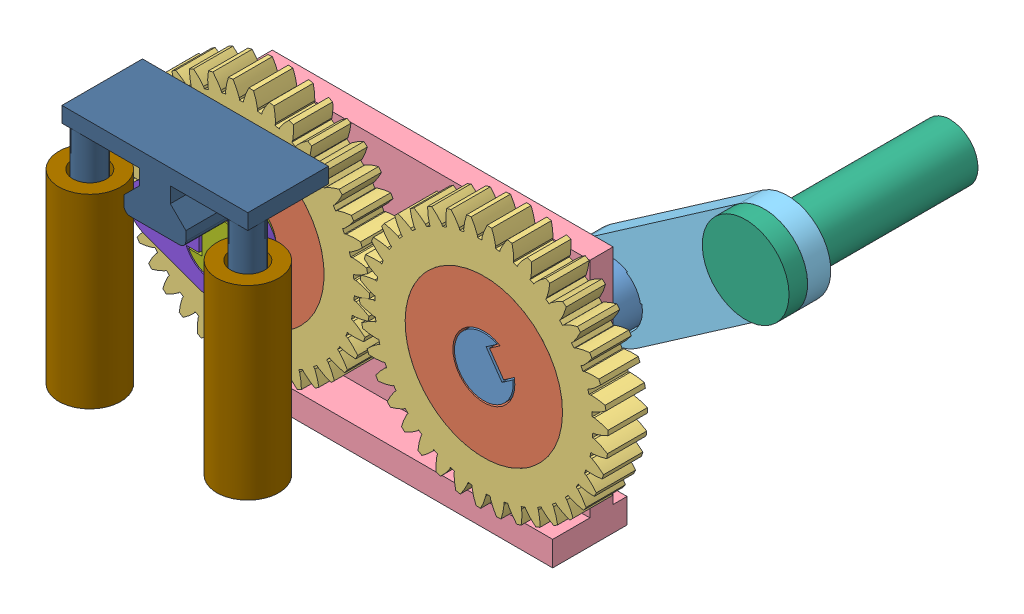
SolidWorks assembly Assem, configuration Default. Lengths in mm.
Overall size (196.54 112.49 136.7).
14 component instances, 10 part files, 30 mates.
Components (placement in the parent):
- crankShaft-1: crankShaft [Default] at (93.481 50.8 17) x (0.570054 -0.821607 0) z (-0.821607 -0.570054 0) size (19 48.7 24.5)
- gear insert-1: gear insert [Default] at (93.481 50.8 17) x (0.570054 -0.821607 0) z (0 0 1) size (50.8 50.8 12.7)
- gear insert-2: gear insert [Default] at (16.519 50.8 17) x (0.999718 0.023754 0) z (0 0 1) size (50.8 50.8 12.7)
- Gear System-1: Gear System [Default] at (25.581 50.8 17) x (0 1 0) z (0 0 1) size (112.49 184 12.7)
  - Gear Design Tutorial-1: Gear Design Tutorial [Default] at (0 9.062 0) x (0.947724 0.319093 0) z (0 0 1) size (80.19 80.19 12.7)
  - Gear Design Tutorial-2: Gear Design Tutorial [Default] at (0 -67.9 0) x (0.791148 0.611625 0) z (0 0 1) size (80.19 80.19 12.7)
- panelStand-1: panelStand [Default] at (55 0 4.5) size (110 80 24)
- turningHandleConnector-1: turningHandleConnector [Default] at (93.481 50.8 -11.5) x (-0.570054 0.821607 0) z (-0.821607 -0.570054 0) size (28 7.5 88)
- turningHandle-1: turningHandle [Default] at (142.7774 85.0032 -11.5) x (0.993504 0.113802 0) z (-0.113802 0.993504 0) size (28 66 28)
- crackArmShaft-1: crackArmShaft [Default] at (16.519 50.8 4.5) x (0.006197 -0.999981 0) z (0 0 -1) size (30 30 41.2)
- crackArmCam-1: crackArmCam [Default] at (16.519 50.8 33.7) x (-0.006197 0.999981 0) z (0 0 1) size (30 43 6)
- camFollowerAligningShaftHolder-1: camFollowerAligningShaftHolder [Default] at (-8.2022 8 55.2) size (20 60 20)
- camFollowerWithAligningShaft-1: camFollowerWithAligningShaft [Default] at (17.2978 65.8 33.7) x (1 0 0) z (0 -1 0) size (60 26 35)
- camFollowerAligningShaftHolder-3: camFollowerAligningShaftHolder [Default] at (42.7978 8 55.2) size (20 60 20)
Mates (geometry in assembly coordinates):
- Concentric1: concentric: cylinder of Gear System-1/Gear Design Tutorial-1 through (16.519 50.8 17) axis (0 0 1) radius 25.4; cylinder of panelStand-1 through (16.519 50.8 12) axis (0 0 -1) radius 10.5
- Concentric2: concentric: cylinder of Gear System-1/Gear Design Tutorial-2 through (93.481 50.8 17) axis (0 0 1) radius 25.4; cylinder of panelStand-1 through (93.481 50.8 12) axis (0 0 -1) radius 10.5
- Concentric3: concentric: cylinder of gear insert-2 through (16.519 50.8 29.7) axis (0 0 -1) radius 25.4; cylinder of Gear System-1/Gear Design Tutorial-1 through (16.519 50.8 17) axis (0 0 1) radius 25.4
- Coincident1: coincident: plane of gear insert-2 through (16.519 50.8 17) normal (0 0 -1); plane of Gear System-1/Gear Design Tutorial-1 through (16.519 50.8 17) normal (0 0 -1)
- Concentric4: concentric: cylinder of gear insert-1 through (93.481 50.8 29.7) axis (0 0 -1) radius 25.4; cylinder of Gear System-1/Gear Design Tutorial-2 through (93.481 50.8 17) axis (0 0 1) radius 25.4
- Coincident2: coincident: plane of gear insert-1 through (93.481 50.8 17) normal (0 0 -1); plane of Gear System-1/Gear Design Tutorial-2 through (93.481 50.8 17) normal (0 0 -1)
- Coincident4: coincident: plane of gear insert-1 through (93.481 50.8 29.7) normal (0 0 1); plane of crankShaft-1 through (93.481 50.8 29.7) normal (0 0 1)
- Concentric7: concentric: cylinder of crankShaft-1 through (93.481 50.8 29.7) axis (0 0 -1) radius 9.5; cylinder of panelStand-1 through (93.481 50.8 12) axis (0 0 -1) radius 10.5
- Parallel2: parallel: line of gear insert-1 through (99.8693 50.3638 29.7) axis (-0.570054 0.821607 0); line of crankShaft-1 through (99.3327 49.383 29.7) axis (-0.570054 0.821607 0)
- Concentric8: concentric: cylinder of crankShaft-1 through (93.481 50.8 29.7) axis (0 0 -1) radius 9.5; cylinder of turningHandleConnector-1 through (93.481 50.8 -19) axis (0 0 1) radius 10
- Coincident6: coincident: plane of crankShaft-1 through (93.481 50.8 -19) normal (0 0 -1); plane of turningHandleConnector-1 through (93.481 50.8 -19) normal (0 0 -1)
- Parallel4: parallel: line of crankShaft-1 through (99.3327 49.383 -19) axis (-0.570054 0.821607 0); line of turningHandleConnector-1 through (95.3088 56.9367 -19) axis (0.570054 -0.821607 0)
- Coincident8: coincident: plane of turningHandleConnector-1 through (93.481 50.8 -11.5) normal (0 0 1); plane of turningHandle-1 through (142.7774 85.0032 -11.5) normal (0 0 -1)
- Concentric9: concentric: cylinder of turningHandleConnector-1 through (142.7774 85.0032 -19) axis (0 0 1) radius 10; cylinder of turningHandle-1 through (142.7774 85.0032 -71.5) axis (0 0 1) radius 9
- Coincident10: coincident: plane of panelStand-1 through (55 0 4.5) normal (0 0 -1); plane of crackArmShaft-1 through (16.519 50.8 4.5) normal (0 0 1)
- Concentric10: concentric: cylinder of panelStand-1 through (16.519 50.8 12) axis (0 0 -1) radius 10.5; cylinder of crackArmShaft-1 through (16.519 50.8 -1.5) axis (0 0 1) radius 15
- Parallel3: parallel: line of crackArmShaft-1 through (12.547 46.2753 39.7) axis (-0.006197 0.999981 0); plane of gear insert-2 through (16.519 50.8 29.7) normal (0 0 1)
- Distance2: distance = 10 mm: plane of gear insert-2 through (16.519 50.8 29.7) normal (0 0 1); plane of crackArmShaft-1 through (16.519 50.8 39.7) normal (0 0 1)
- Coincident13: coincident: plane of crackArmShaft-1 through (16.519 50.8 39.7) normal (0 0 1); plane of crackArmCam-1 through (16.519 50.8 39.7) normal (0 0 1)
- Concentric11: concentric: cylinder of crackArmShaft-1 through (16.519 50.8 39.7) axis (0 0 -1) radius 9.5; cylinder of crackArmCam-1 through (16.519 50.8 39.7) axis (0 0 -1) radius 10
- Parallel5: parallel: line of crackArmShaft-1 through (12.547 46.2753 39.7) axis (-0.006197 0.999981 0); line of crackArmCam-1 through (11.4943 54.7689 39.7) axis (0.006197 -0.999981 0)
- Coincident16: coincident: plane of crackArmCam-1 through (16.519 50.8 33.7) normal (0 0 -1); plane of camFollowerWithAligningShaft-1 through (17.2978 65.8 33.7) normal (0 0 -1)
- Coincident17: coincident: plane of panelStand-1 through (0 8 0) normal (0 1 0); plane of camFollowerAligningShaftHolder-1 through (-8.2022 8 55.2) normal (0 -1 0)
- Concentric12: concentric: cylinder of camFollowerAligningShaftHolder-1 through (-8.2022 68 55.2) axis (0 -1 0) radius 5.5; cylinder of camFollowerWithAligningShaft-1 through (-8.2022 50.8 55.2) axis (0 1 0) radius 4.5
- Concentric13: concentric: cylinder of camFollowerWithAligningShaft-1 through (42.7978 50.8 55.2) axis (0 1 0) radius 4.5; cylinder of camFollowerAligningShaftHolder-3 through (42.7978 68 55.2) axis (0 -1 0) radius 5.5
- Coincident18: coincident: plane of panelStand-1 through (0 8 0) normal (0 1 0); plane of camFollowerAligningShaftHolder-3 through (42.7978 8 55.2) normal (0 -1 0)
- CamMateTangent1: cam tangent: plane of crackArmCam-1; plane of camFollowerWithAligningShaft-1 through (17.2978 65.8 59.7) normal (0 -1 0)
- Coincident19: coincident: point of panelStand-1; point of assembly
- Coincident20: coincident: plane of panelStand-1 through (55 0 12) normal (0 -1 0); plane of assembly through (0 0 0) normal (0 1 0)
- Parallel6: parallel: plane of panelStand-1 through (55 0 24) normal (0 0 1); plane of assembly through (0 0 0) normal (0 0 1)
